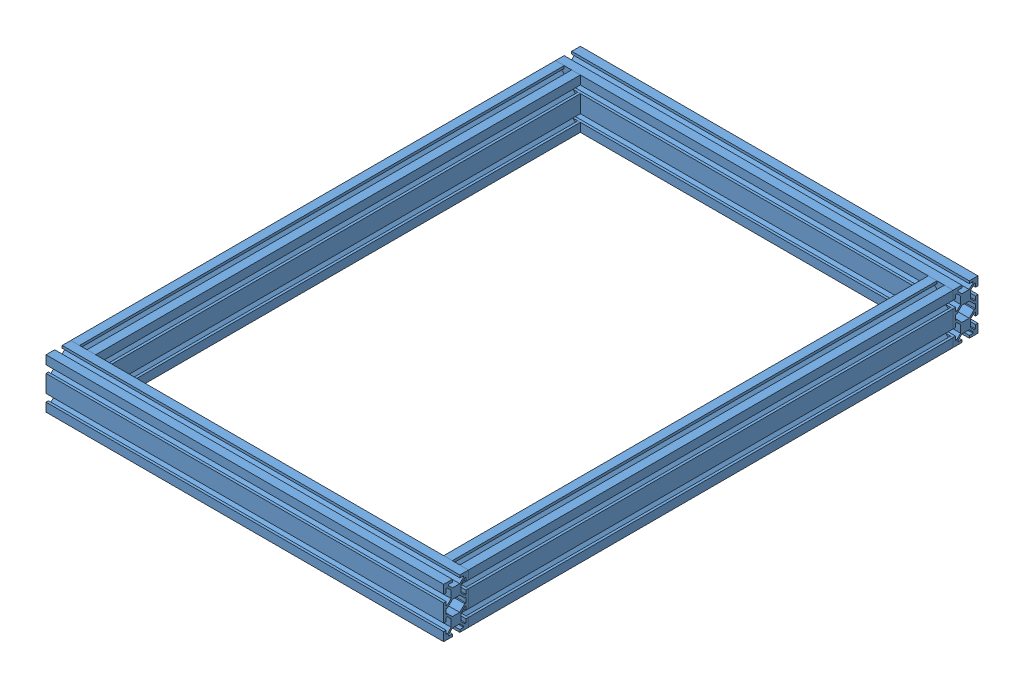
SolidWorks assembly Fence, configuration Default. Lengths in mm.
Overall size (320 40 430).
4 component instances, 1 part files, 6 mates.
Components (placement in the parent):
- 2040_extrusion-1: 2040_extrusion [320] at (0 20 205) x (0 0 1) z (-1 0 0) size (20 40 320)
- 2040_extrusion-2: 2040_extrusion [390] at (150 20 0) size (20 40 390)
- 2040_extrusion-3: 2040_extrusion [390] at (-150 20 0) x (-1 0 0) z (0 0 -1) size (20 40 390)
- 2040_extrusion-4: 2040_extrusion [320] at (0 20 -205) x (0 0 -1) z (1 0 0) size (20 40 320)
Mates (geometry in assembly coordinates):
- Coincident1: coincident anti-aligned: plane of 2040_extrusion-1 through (160 0 195) normal (0 -1 0); plane of assembly through (0 0 0) normal (0 1 0)
- Coincident2: coincident anti-aligned: plane of 2040_extrusion-1 through (0 20 205) normal (-1 0 0); plane of assembly through (0 0 0) normal (1 0 0)
- Coincident3: coincident aligned: plane of 2040_extrusion-2 through (150 20 0) normal (0 0 1); plane of assembly through (0 0 0) normal (0 0 1)
- Coincident4: coincident anti-aligned: plane of 2040_extrusion-2 through (140 0 -195) normal (0 -1 0); plane of assembly through (0 0 0) normal (0 1 0)
- Coincident5: coincident anti-aligned: plane of 2040_extrusion-1 through (160 27 195) normal (0 0 -1); plane of 2040_extrusion-2 through (150 20 195) normal (0 0 1)
- Coincident6: coincident aligned: plane of 2040_extrusion-1 through (160 20 205) normal (1 0 0); plane of 2040_extrusion-2 through (160 13 -195) normal (1 0 0)
